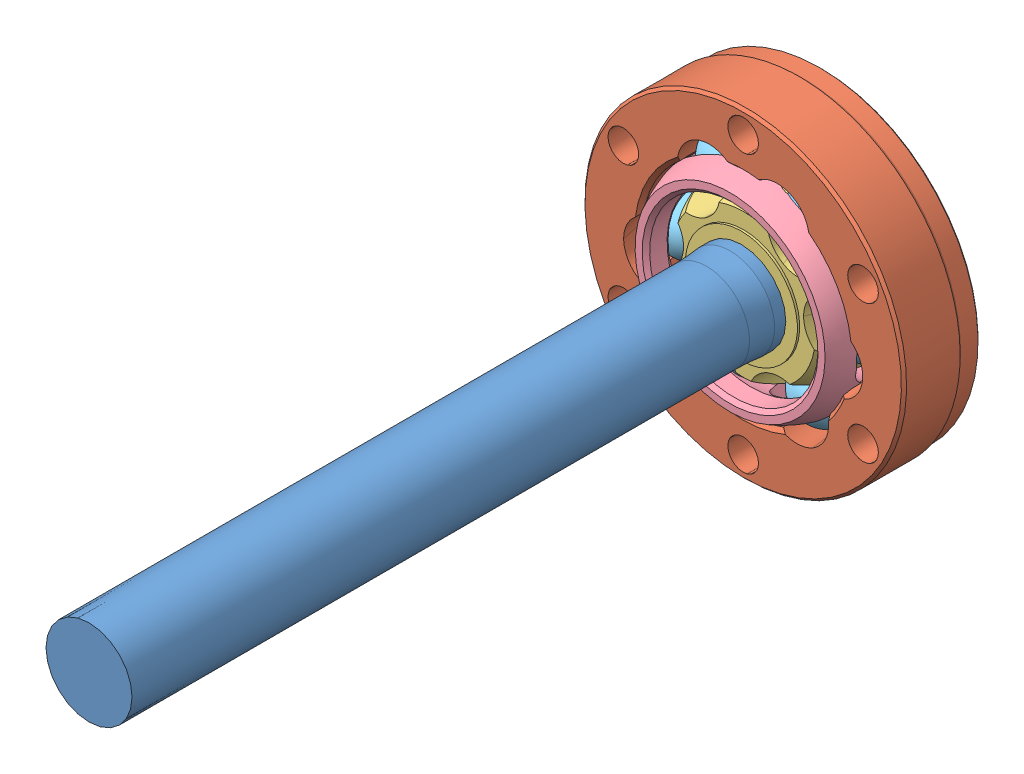
SolidWorks assembly IBKITVL VL, configuration Default. Lengths in mm.
Overall size (86 86 214.4).
12 component instances, 6 part files, 0 mates.
Components (placement in the parent):
- VL1500i Disc Bar End-1: VL1500i Disc Bar End [Default] at origin size (23.8 23.8 200)
- Assembly_1-1: Assembly_1 [Default] at (0 0 14.6) x (0 1 0) z (0 0 1) size (86 86 58)
  - outer_1-1: outer_1 [Default] at origin size (86 86 21)
  - Inner_1-1: Inner_1 [Default] at origin size (48 44.47 22)
  - cage_2-1: cage_2 [Default] at origin size (58 58 58)
  - Ball_1-1: Ball_1 [Default] at (-20.7873 11.9722 0) x (0.890105 0.455465 0.016248) z (-0.011299 -0.013586 0.999844) size (15.88 15.88 15.88)
  - Ball_1-2: Ball_1 [Default] at (-0.0255 23.9884 0) x (0.839497 -0.543121 0.016248) z (-0.017415 0.002992 0.999844) size (15.88 15.88 15.88)
  - Ball_1-3: Ball_1 [Default] at (20.7619 12.0163 0) x (-0.050608 -0.998586 0.016248) z (-0.006117 0.016578 0.999844) size (15.88 15.88 15.88)
  - Ball_1-4: Ball_1 [Default] at (20.7873 -11.9722 0) x (-0.890105 -0.455465 0.016248) z (0.011299 0.013586 0.999844) size (15.88 15.88 15.88)
  - Ball_1-5: Ball_1 [Default] at (0.0255 -23.9884 0) x (-0.839497 0.543121 0.016248) z (0.017415 -0.002992 0.999844) size (15.88 15.88 15.88)
  - Ball_1-6: Ball_1 [Default] at (-20.7619 -12.0163 0) x (0.050608 0.998586 0.016248) z (0.006117 -0.016578 0.999844) size (15.88 15.88 15.88)
- GLi1500 circlip_2-1: GLi1500 circlip_2 [Default] at (0 0 2.4) x (0 -1 0) z (0 0 1) size (22.5 24.63 1.2)
